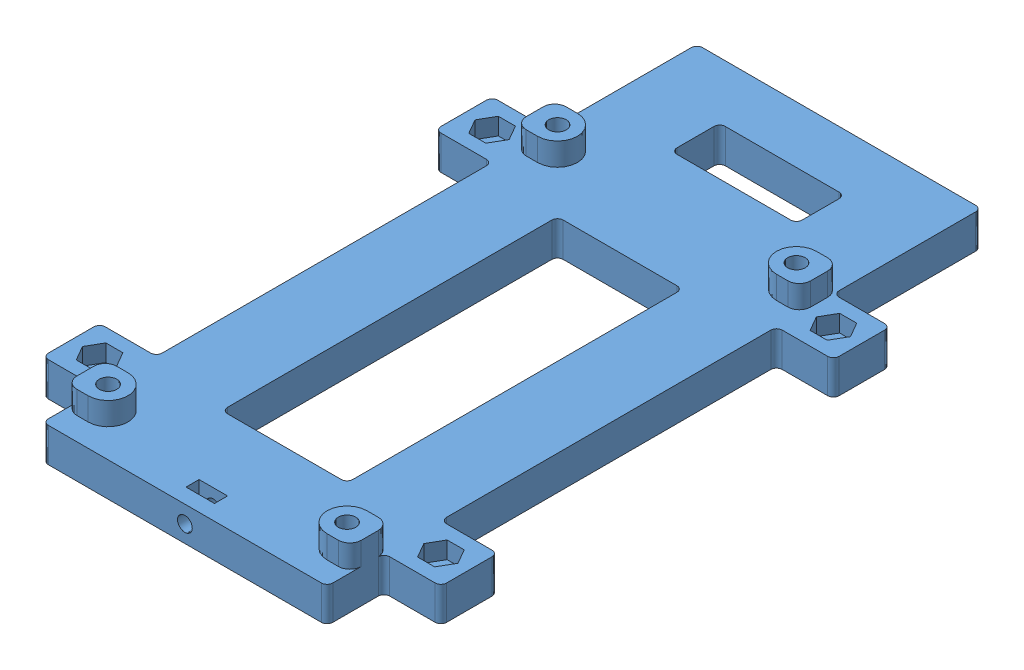
SolidWorks assembly As_tx2_001, configuration Default. Lengths in mm.
Overall size (70 10 115).
4 component instances, 4 part files, 8 mates.
Components (placement in the parent):
- support_tx2_001-1: support_tx2_001 [Default] at origin size (70 10 115)
- Jetson_with_J120-1: Jetson_with_J120 [Default] at (-14.1508 16.3691 -12.356) x (-1 0 0) z (0 1 0) (suppressed, hidden)
- usb-1: usb [Default] at (-1.9501 18.3782 -56) x (1 0 0) z (0 1 0) (suppressed, hidden)
- hdmi_port-1: hdmi_port [Default] at (-17.9999 13.3532 -98.4706) (suppressed, hidden)
Mates (geometry in assembly coordinates):
- Concentric1: concentric aligned: cylinder of support_tx2_001-1 through (-21 6 50) axis (0 -1 0) radius 1.55; cylinder of Jetson_with_J120-1 through (-21 10 50) axis (0 -1 0) radius 1.6
- Concentric2: concentric aligned: cylinder of support_tx2_001-1 through (21 6 50) axis (0 -1 0) radius 1.55; cylinder of Jetson_with_J120-1 through (21 10 50) axis (0 -1 0) radius 1.6
- Distance1: distance = 4 mm anti-aligned: plane of support_tx2_001-1 through (0 6 0) normal (0 1 0); plane of Jetson_with_J120-1 through (-25 10 -56) normal (0 -1 0)
- Coincident3: coincident aligned: plane of Jetson_with_J120-1 through (4.5499 26.4782 -55.5001) normal (1 0 0); plane of usb-1 through (4.5499 9.8782 -101) normal (1 0 0)
- Coincident5: coincident aligned: plane of Jetson_with_J120-1 through (-8.1501 26.8782 -55.5001) normal (0 1 0); plane of usb-1 through (-8.4501 26.8782 -101) normal (0 1 0)
- Coincident6: coincident anti-aligned: plane of Jetson_with_J120-1 through (25 10 -56) normal (0 0 -1); plane of usb-1 through (-1.9501 18.3782 -56) normal (0 0 1)
- Coincident7: coincident aligned: plane of Jetson_with_J120-1 through (-13.1599 14.8532 -48.5499) normal (0 1 0); plane of hdmi_port-1 through (-23.9999 14.8532 -48.4706) normal (0 1 0)
- Coincident8: coincident aligned: plane of Jetson_with_J120-1 through (-23.9999 14.4932 -48.5499) normal (-1 0 0); plane of hdmi_port-1 through (-23.9999 14.8532 -48.4706) normal (-1 0 0)
